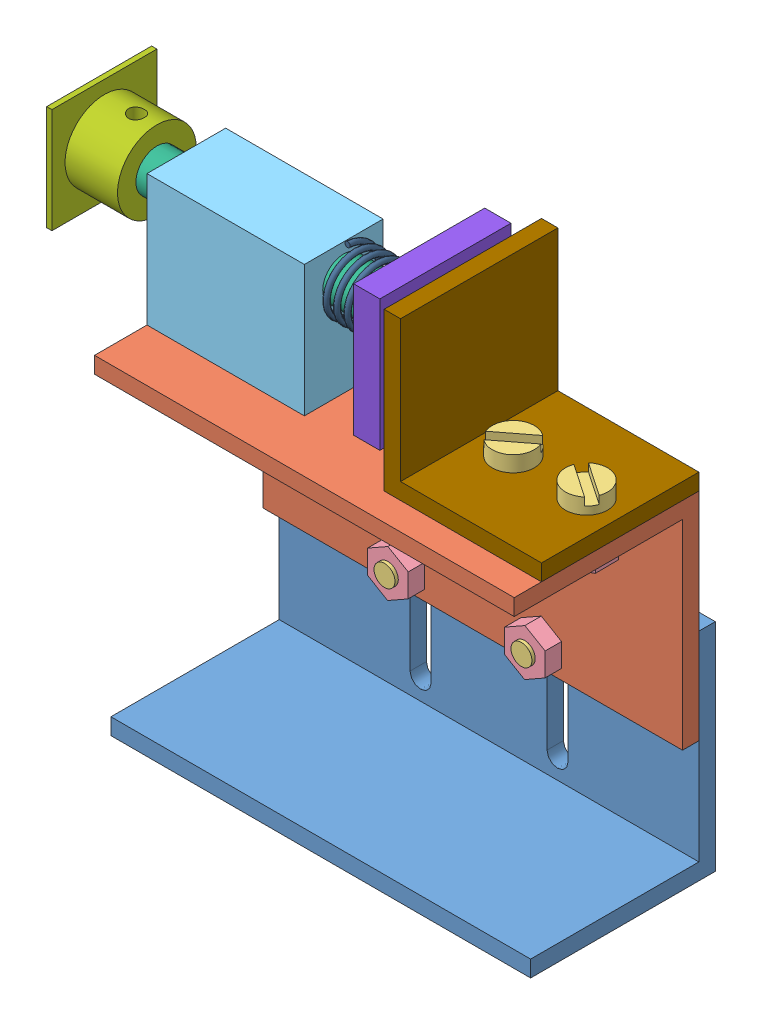
SolidWorks assembly Suporte do piezoelétrico, configuration Valor predeterminado. Lengths in mm.
Overall size (96.61 95.85 41.32).
18 component instances, 10 part files, 37 mates.
Components (placement in the parent):
- Base-1: Base [Default] at (-50.787 -14.5857 97.599) size (80 41.23 35.2)
- Mesa-1: Mesa [Default] at (29.213 43.5143 100.724) x (-1 0 0) z (0 0 1) size (80 41.23 35.2)
- Parafuso Padrao M4-1: Parafuso Padrao M4 [Default] at (-23.837 9.621 62.401) x (1 0 0) z (0 1 0) size (8 13 8)
- Parafuso Padrao M4-2: Parafuso Padrao M4 [Default] at (2.263 9.621 62.401) x (-0.416199 0.909273 0) z (-0.909273 -0.416199 0) size (8 13 8)
- Porca M4-1: Porca M4 [Default] at (2.263 9.621 71.776) x (1 0 0) z (0 1 0) size (7.78 3.12 8.95)
- Porca M4-2: Porca M4 [Default] at (-23.837 9.621 71.776) x (1 0 0) z (0 1 0) size (7.78 3.12 8.95)
- Guia de teflon-1: Guia de teflon [Valor predeterminado] at (-73.217 71.6393 90.724) x (-1 0 0) z (0 -1 0) size (30 15 25)
- Parafuso Padrao M4-3: Parafuso Padrao M4 [Default] at (-45.5601 43.5143 83.125) x (0.99697 0 -0.077792) z (-0.077792 0 -0.99697) size (8 13 8)
- Parafuso Padrao M4-4: Parafuso Padrao M4 [Default] at (-27.7313 43.5143 83.125) x (0.99697 0 -0.077792) z (-0.077792 0 -0.99697) size (8 13 8)
- Eixo-1: Eixo [Valor predeterminado] at (-6.4008 65.6393 83.224) x (0 -0.484969 0.874532) z (-1 0 0) size (8 8 60)
- Placa do espelho-1: Placa do espelho [Valor predeterminado] at (-56.4008 65.6393 83.224) x (0 0 1) z (-1 0 0) size (20 20 11)
- Placa de cobre-1: Placa de cobre [Valor predeterminado] at (-1.4058 53.1393 95.724) x (0 0 1) z (-1 0 0) size (25 25 5)
- Apoio do piezo-1: Apoio do piezo [Valor predeterminado] at (29.213 46.6393 65.526) size (30 30 30)
- Parafuso Padrao M4-5: Parafuso Padrao M4 [Default] at (8.8321 49.7643 80.526) x (-0.609617 0 -0.792696) z (0.792696 0 -0.609617) size (8 13 8)
- Parafuso Padrao M4-6: Parafuso Padrao M4 [Default] at (22.7953 49.7643 80.526) x (0.563085 0 -0.826399) z (0.826399 0 0.563085) size (8 13 8)
- Porca M4-3: Porca M4 [Default] at (8.8321 40.3893 80.526) size (7.78 3.12 8.95)
- Porca M4-4: Porca M4 [Default] at (22.7953 40.3893 80.526) size (7.78 3.12 8.95)
- Mola do guia linear-1: Mola do guia linear [Default] at (-6.1058 65.9905 83.1743) x (0 0 1) z (-1 0 0) size (13.86 12.29 15)
Mates (geometry in assembly coordinates):
- Coincidente1: coincident anti-aligned: plane of Base-1 through (29.213 -14.5857 65.526) normal (0 0 1); plane of Mesa-1 through (-50.787 43.5143 65.526) normal (0 0 -1)
- Distância1: distance = 20 mm anti-aligned: plane of Base-1 through (29.213 -14.5857 97.599) normal (0 1 0); plane of Mesa-1 through (-50.787 5.4143 68.651) normal (0 -1 0)
- Coincidente3: coincident aligned: plane of Base-1 through (-50.787 -14.5857 62.401) normal (-1 0 0); plane of Mesa-1 through (-50.787 43.5143 65.526) normal (-1 0 0)
- Concêntrico1: concentric aligned: cylinder of Mesa-1 through (-23.837 9.621 75.526) axis (0 0 -1) radius 2; cylinder of Parafuso Padrao M4-1 through (-23.837 9.621 72.401) axis (0 0 -1) radius 2
- Concêntrico2: concentric aligned: cylinder of Mesa-1 through (2.263 9.621 75.526) axis (0 0 -1) radius 2; cylinder of Parafuso Padrao M4-2 through (2.263 9.621 72.401) axis (0 0 -1) radius 2
- Coincidente4: coincident anti-aligned: plane of Base-1 through (29.213 -14.5857 62.401) normal (0 0 -1); plane of Parafuso Padrao M4-1 through (-23.837 9.621 62.401) normal (0 0 1)
- Coincidente5: coincident anti-aligned: plane of Base-1 through (29.213 -14.5857 62.401) normal (0 0 -1); plane of Parafuso Padrao M4-2 through (2.263 9.621 62.401) normal (0 0 1)
- Concêntrico3: concentric anti-aligned: cylinder of Parafuso Padrao M4-1 through (-23.837 9.621 72.401) axis (0 0 -1) radius 2; cylinder of Porca M4-2 through (-23.837 9.621 68.651) axis (0 0 1) radius 2
- Concêntrico4: concentric anti-aligned: cylinder of Parafuso Padrao M4-2 through (2.263 9.621 72.401) axis (0 0 -1) radius 2; cylinder of Porca M4-1 through (2.263 9.621 68.651) axis (0 0 1) radius 2
- Coincidente6: coincident anti-aligned: plane of Mesa-1 through (-50.787 43.5143 68.651) normal (0 0 1); plane of Porca M4-1 through (6.1534 11.8315 68.651) normal (0 0 -1)
- Coincidente7: coincident anti-aligned: plane of Mesa-1 through (-50.787 43.5143 68.651) normal (0 0 1); plane of Porca M4-2 through (-19.9466 11.8315 68.651) normal (0 0 -1)
- Coincidente8: coincident anti-aligned: plane of Mesa-1 through (-50.787 46.6393 100.724) normal (0 1 0); plane of Guia de teflon-1 through (-73.217 46.6393 90.724) normal (0 -1 0)
- Coincidente9: coincident aligned: plane of Mesa-1 through (-50.787 43.5143 65.526) normal (-1 0 0); plane of Guia de teflon-1 through (-50.787 46.6393 90.724) normal (-1 0 0)
- Distância2: distance = 10 mm aligned: plane of Mesa-1 through (-50.787 46.6393 100.724) normal (0 0 1); plane of Guia de teflon-1 through (-50.787 46.6393 90.724) normal (0 0 1)
- Concêntrico5: concentric anti-aligned: cylinder of Mesa-1 through (-27.7313 5.4143 83.125) axis (0 1 0) radius 2; cylinder of Parafuso Padrao M4-4 through (-27.7313 53.5143 83.125) axis (0 -1 0) radius 2
- Concêntrico6: concentric anti-aligned: cylinder of Mesa-1 through (-45.5601 5.4143 83.125) axis (0 1 0) radius 2; cylinder of Parafuso Padrao M4-3 through (-45.5601 53.5143 83.125) axis (0 -1 0) radius 2
- Coincidente11: coincident anti-aligned: plane of Mesa-1 through (-50.787 43.5143 100.724) normal (0 -1 0); plane of Parafuso Padrao M4-3 through (-45.5601 43.5143 83.125) normal (0 1 0)
- Coincidente12: coincident anti-aligned: plane of Mesa-1 through (-50.787 43.5143 100.724) normal (0 -1 0); plane of Parafuso Padrao M4-4 through (-27.7313 43.5143 83.125) normal (0 1 0)
- Concêntrico7: concentric anti-aligned: cylinder of Guia de teflon-1 through (-20.787 65.6393 83.224) axis (-1 0 0) radius 4; cylinder of Eixo-1 through (-66.4008 65.6393 83.224) axis (1 0 0) radius 4
- Concêntrico8: concentric aligned: cylinder of Eixo-1 through (-66.4008 65.6393 83.224) axis (1 0 0) radius 4; cylinder of Placa do espelho-1 through (-66.4008 65.6393 83.224) axis (1 0 0) radius 4
- Coincidente13: coincident anti-aligned: plane of Eixo-1 through (-66.4008 65.6393 83.224) normal (-1 0 0); plane of Placa do espelho-1 through (-66.4008 65.6393 83.224) normal (1 0 0)
- Paralelo1: parallel aligned: plane of Guia de teflon-1 through (-73.217 71.6393 90.724) normal (0 1 0); plane of Placa do espelho-1 through (-67.4008 75.6393 73.224) normal (0 1 0)
- Concêntrico9: concentric anti-aligned: cylinder of Eixo-1 through (-66.4008 65.6393 83.224) axis (1 0 0) radius 4; circle of Placa de cobre-1
- Coincidente16: coincident anti-aligned: plane of Eixo-1 through (-6.4008 65.6393 83.224) normal (1 0 0); plane of Placa de cobre-1 through (-6.4008 65.6393 83.224) normal (-1 0 0)
- Paralelo2: parallel aligned: plane of Guia de teflon-1 through (-73.217 71.6393 90.724) normal (0 1 0); plane of Placa de cobre-1 through (-6.4058 78.1393 95.724) normal (0 1 0)
- Coincidente18: coincident anti-aligned: plane of Mesa-1 through (-50.787 46.6393 100.724) normal (0 1 0); plane of Apoio do piezo-1 through (29.213 46.6393 95.526) normal (0 -1 0)
- Coincidente19: coincident aligned: plane of Mesa-1 through (29.213 43.5143 65.526) normal (1 0 0); plane of Apoio do piezo-1 through (29.213 49.7643 95.526) normal (1 0 0)
- Coincidente20: coincident aligned: plane of Mesa-1 through (-50.787 43.5143 65.526) normal (0 0 -1); plane of Apoio do piezo-1 through (29.213 46.6393 65.526) normal (0 0 -1)
- Concêntrico12: concentric aligned: cylinder of Apoio do piezo-1 through (8.8321 19.7643 80.526) axis (0 1 0) radius 2; cylinder of Parafuso Padrao M4-5 through (8.8321 39.7643 80.526) axis (0 1 0) radius 2
- Coincidente22: coincident anti-aligned: plane of Apoio do piezo-1 through (29.213 49.7643 95.526) normal (0 1 0); plane of Parafuso Padrao M4-5 through (8.8321 49.7643 80.526) normal (0 -1 0)
- Concêntrico13: concentric aligned: cylinder of Apoio do piezo-1 through (22.7953 19.7643 80.526) axis (0 1 0) radius 2; cylinder of Parafuso Padrao M4-6 through (22.7953 39.7643 80.526) axis (0 1 0) radius 2
- Coincidente23: coincident anti-aligned: plane of Apoio do piezo-1 through (29.213 49.7643 95.526) normal (0 1 0); plane of Parafuso Padrao M4-6 through (22.7953 49.7643 80.526) normal (0 -1 0)
- Concêntrico14: concentric anti-aligned: cylinder of Parafuso Padrao M4-6 through (22.7953 39.7643 80.526) axis (0 1 0) radius 2; cylinder of Porca M4-4 through (22.7953 43.5143 80.526) axis (0 -1 0) radius 2
- Concêntrico15: concentric anti-aligned: cylinder of Parafuso Padrao M4-5 through (8.8321 39.7643 80.526) axis (0 1 0) radius 2; cylinder of Porca M4-3 through (8.8321 43.5143 80.526) axis (0 -1 0) radius 2
- Coincidente24: coincident anti-aligned: plane of Mesa-1 through (-50.787 43.5143 100.724) normal (0 -1 0); plane of Porca M4-4 through (26.6857 43.5143 82.7364) normal (0 1 0)
- Coincidente25: coincident anti-aligned: plane of Mesa-1 through (-50.787 43.5143 100.724) normal (0 -1 0); plane of Porca M4-3 through (12.7225 43.5143 82.7364) normal (0 1 0)
- Coincidente26: coincident anti-aligned: plane of Placa de cobre-1 through (-6.4058 53.1393 95.724) normal (-1 0 0); plane of Mola do guia linear-1 through (-6.4058 65.9905 83.1743) normal (1 0 0)
